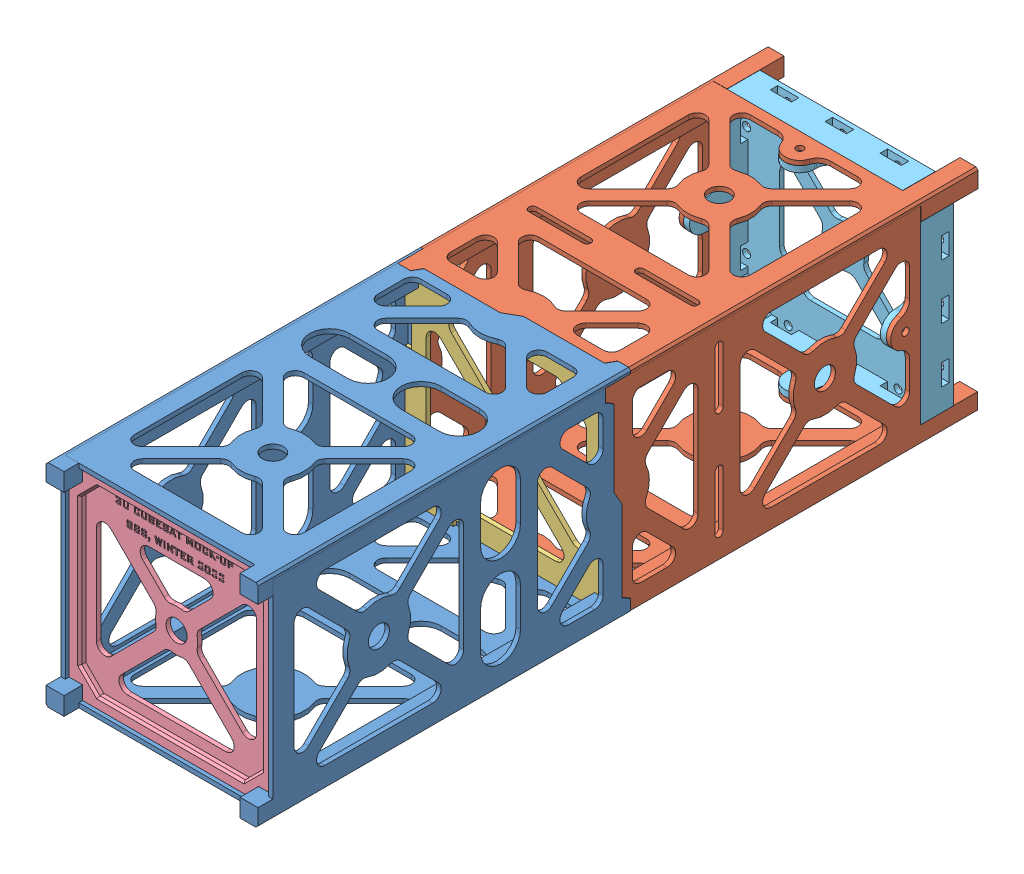
SolidWorks assembly 3U_Chassis_Printable_Mockup, configuration Default. Lengths in mm.
Overall size (100.1 100.1 339.6).
11 component instances, 5 part files, 27 mates.
Components (placement in the parent):
- Side_Bottom-1: Side_Bottom [Default] at (43.6506 121.8864 118.7346) size (97.9 8.5 175.8)
- Side_Bottom-2: Side_Bottom [Default] at (45.7506 221.8864 118.7346) x (-1 0 0) z (0 0 1) size (97.9 8.5 175.8)
- Side_Bottom-3: Side_Bottom [Default] at (94.7006 170.8364 118.7346) x (0 1 0) z (0 0 1) size (97.9 8.5 175.8)
- Side_Bottom-4: Side_Bottom [Default] at (-5.2994 172.9364 118.7346) x (0 -1 0) z (0 0 1) size (97.9 8.5 175.8)
- Side_top-1: Side_top [Default] at (45.7506 219.7864 122.7346) x (-1 0 0) z (0 0 -1) size (97.9 8.5 175.8)
- Center_Support-1: Center_Support [Default] at (44.6006 171.7864 123.2846) x (1 0 0) z (0 1 0) size (95.6 5 95.6)
- Side_top-2: Side_top [Default] at (92.4006 170.8364 122.7346) x (0 1 0) z (0 0 -1) size (97.9 8.5 175.8)
- Side_top-3: Side_top [Default] at (-3.1994 172.9364 122.7346) x (0 -1 0) z (0 0 -1) size (97.9 8.5 175.8)
- Side_top-4: Side_top [Default] at (43.6506 123.9864 122.7346) x (1 0 0) z (0 0 -1) size (97.9 8.5 175.8)
- Bottom_Support-1: Bottom_Support [Default] at (44.6006 171.7864 276.7346) x (1 0 0) z (0 -1 0) size (95.6 5 95.6)
- Top_Support-1: Top_Support [Default] at (44.6006 171.7864 -37.6654) x (1 0 0) z (0 -1 0) size (100 29.6 100)
Mates (geometry in assembly coordinates):
- Coincident15: coincident anti-aligned: line of Side_Bottom-2 through (-3.1994 221.8864 126.7346) axis (0 0 1); line of Side_Bottom-4 through (-3.1994 221.8864 283.5346) axis (0 0 -1)
- Coincident16: coincident aligned: line of Side_Bottom-2 through (-3.1994 221.8864 283.5346) axis (1 0 0); line of Side_Bottom-4 through (-3.1994 221.8864 283.5346) axis (1 0 0)
- Coincident17: coincident aligned: line of Side_Bottom-2 through (94.7006 219.7864 283.5346) axis (0 -1 0); line of Side_Bottom-3 through (94.7006 219.7864 283.5346) axis (0 -1 0)
- Coincident18: coincident anti-aligned: line of Side_Bottom-2 through (94.7006 219.7864 283.5346) axis (0 0 -1); line of Side_Bottom-3 through (94.7006 219.7864 126.7346) axis (0 0 1)
- Coincident19: coincident aligned: line of Side_Bottom-1 through (92.6006 121.8864 283.5346) axis (-1 0 0); line of Side_Bottom-3 through (92.6006 121.8864 283.5346) axis (-1 0 0)
- Coincident20: coincident anti-aligned: line of Side_Bottom-1 through (92.6006 121.8864 126.7346) axis (0 0 1); line of Side_Bottom-3 through (92.6006 121.8864 283.5346) axis (0 0 -1)
- Distance6: distance = 0 mm anti-aligned: plane of Center_Support-1 through (3.2006 123.9864 121.1846) normal (0 -1 0); plane of Side_Bottom-1 through (43.6506 123.9864 118.7346) normal (0 1 0)
- Coincident23: coincident anti-aligned: plane of Side_Bottom-1 through (19.7006 126.9864 119.4846) normal (0 0 -1); plane of Center_Support-1 through (19.5006 126.9864 119.4846) normal (0 0 1)
- Coincident24: coincident anti-aligned: plane of Side_Bottom-4 through (-3.1994 172.9364 118.7346) normal (1 0 0); plane of Center_Support-1 through (-3.1994 213.1864 121.1846) normal (-1 0 0)
- Distance7: distance = 0 mm anti-aligned: plane of Side_top-1 through (45.7506 219.7864 122.7346) normal (0 -1 0); plane of Side_Bottom-4 through (-5.2994 219.7864 118.7346) normal (0 1 0)
- Coincident25: coincident anti-aligned: plane of Side_Bottom-4 through (-3.1994 172.9364 118.7346) normal (1 0 0); plane of Side_top-1 through (-3.1994 221.8864 122.7346) normal (-1 0 0)
- Coincident26: coincident anti-aligned: plane of Side_Bottom-2 through (45.7506 219.7864 126.7346) normal (0 0 -1); plane of Side_top-1 through (45.7506 221.8864 126.7346) normal (0 0 1)
- Coincident28: coincident anti-aligned: plane of Side_Bottom-3 through (92.6006 170.8364 126.7346) normal (0 0 -1); plane of Side_top-2 through (94.5006 170.8364 126.7346) normal (0 0 1)
- Coincident29: coincident anti-aligned: plane of Center_Support-1 through (92.4006 130.3864 121.1846) normal (1 0 0); plane of Side_top-2 through (92.4006 170.8364 122.7346) normal (-1 0 0)
- Coincident30: coincident anti-aligned: plane of Side_Bottom-2 through (45.7506 219.7864 118.7346) normal (0 -1 0); plane of Side_top-2 through (94.5006 219.7864 122.7346) normal (0 1 0)
- Coincident31: coincident anti-aligned: plane of Side_Bottom-1 through (-5.2994 130.3864 120.7346) normal (0 0 -1); plane of Side_top-4 through (3.2006 130.3864 120.7346) normal (0 0 1)
- Coincident32: coincident anti-aligned: plane of Side_Bottom-1 through (43.6506 123.9864 118.7346) normal (0 1 0); plane of Side_top-4 through (43.6506 123.9864 122.7346) normal (0 -1 0)
- Coincident33: coincident anti-aligned: plane of Side_Bottom-3 through (92.6006 170.8364 118.7346) normal (-1 0 0); plane of Side_top-4 through (92.6006 121.8864 122.7346) normal (1 0 0)
- Coincident34: coincident anti-aligned: plane of Side_Bottom-4 through (3.2006 221.8864 120.7346) normal (0 0 -1); plane of Side_top-3 through (3.2006 213.3864 120.7346) normal (0 0 1)
- Coincident35: coincident anti-aligned: plane of Side_top-1 through (45.7506 219.7864 122.7346) normal (0 -1 0); plane of Side_top-3 through (-3.1994 219.7864 122.7346) normal (0 1 0)
- Coincident36: coincident anti-aligned: plane of Side_top-3 through (-3.1994 172.9364 122.7346) normal (1 0 0); plane of Side_top-4 through (-3.1994 123.9864 122.7346) normal (-1 0 0)
- Coincident38: coincident anti-aligned: plane of Side_Bottom-1 through (43.6506 123.9864 118.7346) normal (0 1 0); plane of Bottom_Support-1 through (86.0006 123.9864 278.8346) normal (0 -1 0)
- Coincident39: coincident anti-aligned: plane of Side_Bottom-4 through (-3.1994 172.9364 118.7346) normal (1 0 0); plane of Bottom_Support-1 through (-3.1994 130.3864 278.8346) normal (-1 0 0)
- Coincident40: coincident anti-aligned: plane of Side_Bottom-3 through (89.6006 186.8864 280.5346) normal (0 0 1); plane of Bottom_Support-1 through (89.4006 196.8864 280.5346) normal (0 0 -1)
- Coincident41: coincident anti-aligned: plane of Side_top-2 through (86.0006 170.8364 122.7346) normal (-1 0 0); plane of Top_Support-1 through (86.0006 130.3864 -35.5654) normal (1 0 0)
- Coincident42: coincident anti-aligned: plane of Side_top-2 through (94.5006 130.3864 122.7346) normal (0 1 0); plane of Top_Support-1 through (94.6006 130.3864 -35.5654) normal (0 -1 0)
- Coincident43: coincident anti-aligned: plane of Side_top-2 through (86.0006 130.3864 -22.0654) normal (0 0 -1); plane of Top_Support-1 through (44.6006 171.7864 -22.0654) normal (0 0 1)
